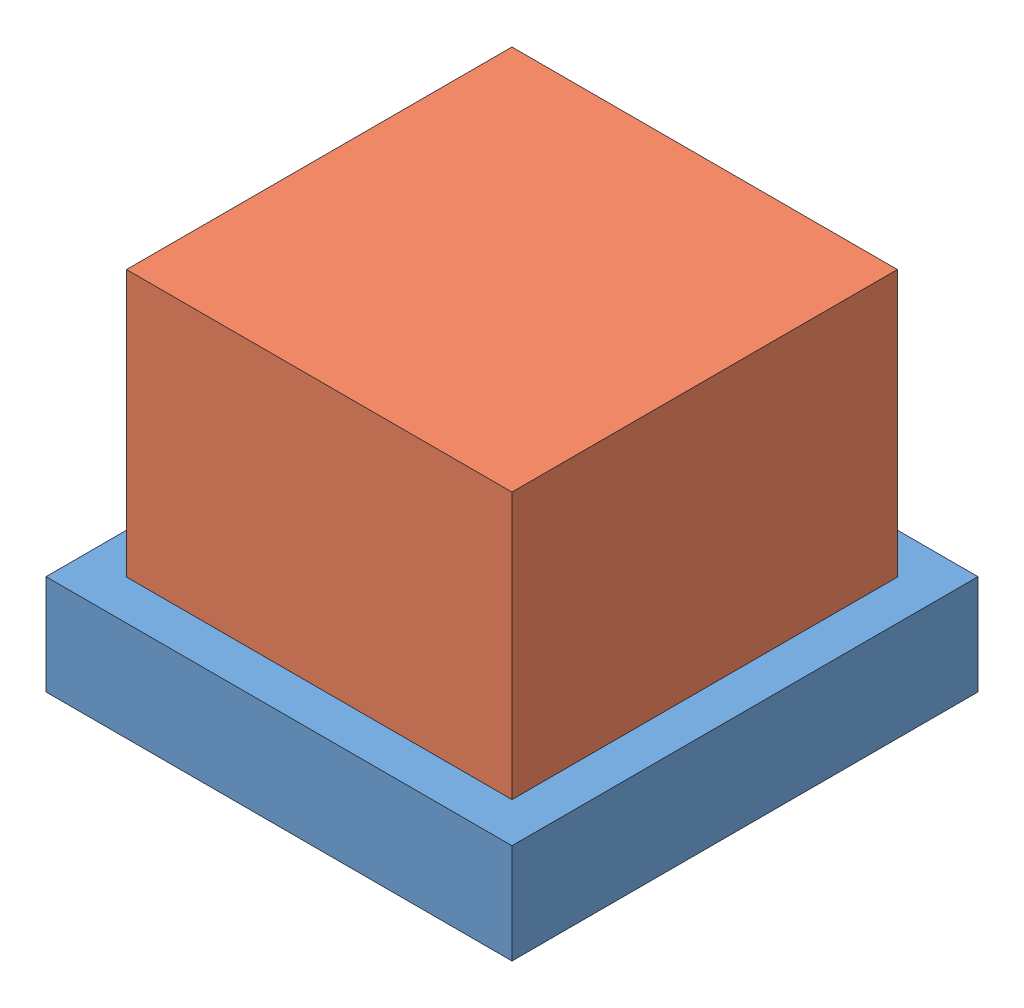
SolidWorks assembly 装配体1, configuration 默认. Lengths in mm.
Overall size (70 55 70).
2 component instances, 2 part files, 2 mates.
Components (placement in the parent):
- Shell-1: Shell [默认] at (-35.7381 -8.0536 35) size (70 15 70)
- Shell_cover-1: Shell_cover [默认] at (25.2539 46.9464 96) x (-1 0 0) z (0 0 1) size (57.9 43 57.9)
Mates (geometry in assembly coordinates):
- 重合1: coincident anti-aligned: plane of Shell-1 through (-35.7381 3.9464 35) normal (0 1 0); plane of Shell_cover-1 through (25.2539 3.9464 96) normal (0 -1 0)
- 重合2: coincident anti-aligned: plane of Shell-1 through (28.2619 3.9464 99) normal (0 0 -1); plane of Shell_cover-1 through (28.2539 43.9464 99) normal (0 0 1)
